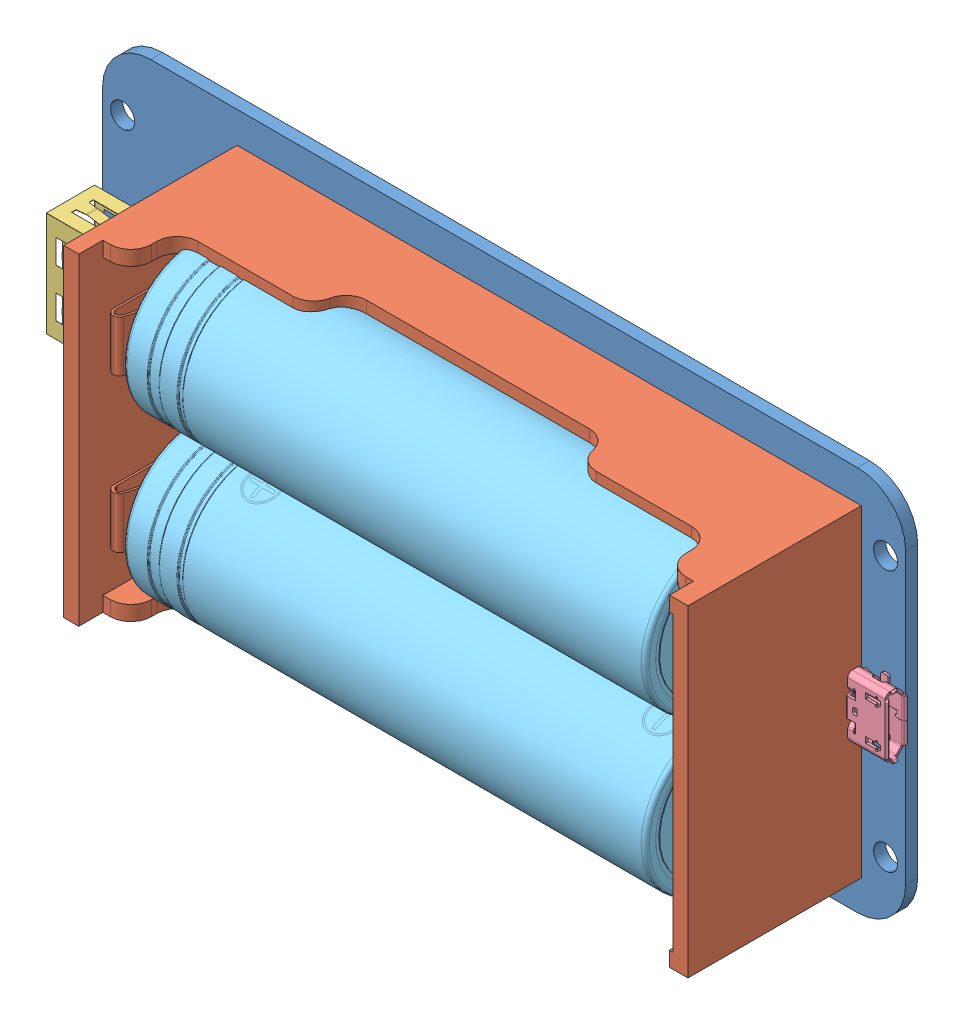
SolidWorks assembly DP_no_screws, configuration Predeterminado. Lengths in mm.
Overall size (100.29 48 25.96).
6 component instances, 5 part files, 18 mates.
Components (placement in the parent):
- 18650_Battery Holder_PCB-1: 18650_Battery Holder_PCB [Predeterminado] at (4.2336 3.5444 100) size (100 48 1.5)
- 18650_Battery Holder-1: 18650_Battery Holder [Predeterminado] at (15.2659 0.4104 101.5) x (1 0 0) z (0 -1 0) size (77.72 24.77 40.13)
- USB Typ A Buchse-1: USB Typ A Buchse [Predeterminado] at (-22.3556 8.2697 102.5) x (-1 0 0) z (0 0 1) size (17 15.6 7.7)
- micro_usb-1: micro_usb [Predeterminado] at (57.3509 0.2464 101.3932) x (0 1 0) z (1 0 0) size (7.98 2.76 5.43)
- 18650-1: 18650 [Default] at (47.6086 10.1819 112.7066) x (0 0.035864 -0.999357) z (0 0.999357 0.035864) size (18.4 65 18.4)
- 18650-2: 18650 [Default] at (47.6086 -9.3611 112.7066) x (0 0.951827 0.306637) z (0 -0.306637 0.951827) size (18.4 65 18.4)
Mates (geometry in assembly coordinates):
- Coincidente1: coincident: plane of 18650_Battery Holder_PCB-1 through (53.6444 18.3444 101.5) normal (0 0 1); plane of 18650_Battery Holder-1 through (15.2659 0.4104 101.5) normal (0 0 -1)
- Distancia2: distance = 0.1 mm: plane of micro_usb-1 through (55.4709 -14.0274 101.6) normal (0 0 -1); plane of 18650_Battery Holder_PCB-1 through (53.6444 18.3444 101.5) normal (0 0 1)
- Paralelo2: parallel: plane of 18650_Battery Holder_PCB-1 through (-40.3556 -17.6556 101.5) normal (-1 0 0); plane of micro_usb-1 through (54.5009 6.001 104.4784) normal (-1 0 0)
- Coincidente6: coincident: plane of 18650_Battery Holder_PCB-1 through (53.6444 18.3444 101.5) normal (0 0 1); plane of USB Typ A Buchse-1 through (-27.3556 7.8697 101.5) normal (0 0 -1)
- Paralelo4: parallel: plane of 18650_Battery Holder_PCB-1 through (53.6444 -23.6556 101.5) normal (0 -1 0); plane of USB Typ A Buchse-1 through (-26.3556 -4.7303 102.5) normal (0 -1 0)
- Coincidente8: coincident: plane of 18650_Battery Holder_PCB-1 through (-40.3556 -17.6556 101.5) normal (-1 0 0); plane of USB Typ A Buchse-1 through (-40.3556 1.7848 105.4949) normal (-1 0 0)
- Bloquear1: lock: unknown of 18650_Battery Holder_PCB-1; unknown of USB Typ A Buchse-1
- Tangente3: tangent: plane of 18650_Battery Holder-1 through (15.2659 0.4104 103.5066) normal (0 0 1); cylinder of 18650-1 through (47.6086 10.1819 112.7066) axis (-1 0 0) radius 9.2
- Tangente4: tangent: plane of 18650_Battery Holder-1 through (-21.7165 0.9819 113.438) normal (0 1 0); cylinder of 18650-1 through (47.6086 10.1819 112.7066) axis (-1 0 0) radius 9.2
- Tangente5: tangent: plane of 18650_Battery Holder-1 through (15.2659 0.4104 103.5066) normal (0 0 1); cylinder of 18650-2 through (47.6086 -9.3611 112.7066) axis (-1 0 0) radius 9.2
- Tangente6: tangent: plane of 18650_Battery Holder-1 through (52.2483 -0.1611 113.438) normal (0 -1 0); cylinder of 18650-2 through (47.6086 -9.3611 112.7066) axis (-1 0 0) radius 9.2
- Coincidente11: coincident: plane of 18650-1 through (47.6086 10.1819 112.7066) normal (1 0 0); plane of 18650-2 through (47.6086 -9.3611 112.7066) normal (1 0 0)
- Concéntrica2: concentric: circle of 18650_Battery Holder_PCB-1; circle of ?
- Coincidente12: coincident: plane of 18650_Battery Holder_PCB-1 through (53.6444 18.3444 100) normal (0 0 -1); plane of ? through (-37.8556 -15.9056 100) normal (0 0 1)
- Coincidente15: coincident: plane of 18650_Battery Holder_PCB-1 through (53.6444 18.3444 101.5) normal (0 0 1); plane of ? through (-37.8556 -14.3056 101.5) normal (0 0 -1)
- Concéntrica4: concentric: circle of 18650_Battery Holder_PCB-1; circle of ?
- Distancia4: distance = 1 mm: plane of ? through (-37.8556 -15.9056 94) normal (0 0 -1); plane of ? through (-37.8556 -15.9056 93) normal (0 0 1)
- Concéntrica8: concentric: circle of ?; circle of ?
